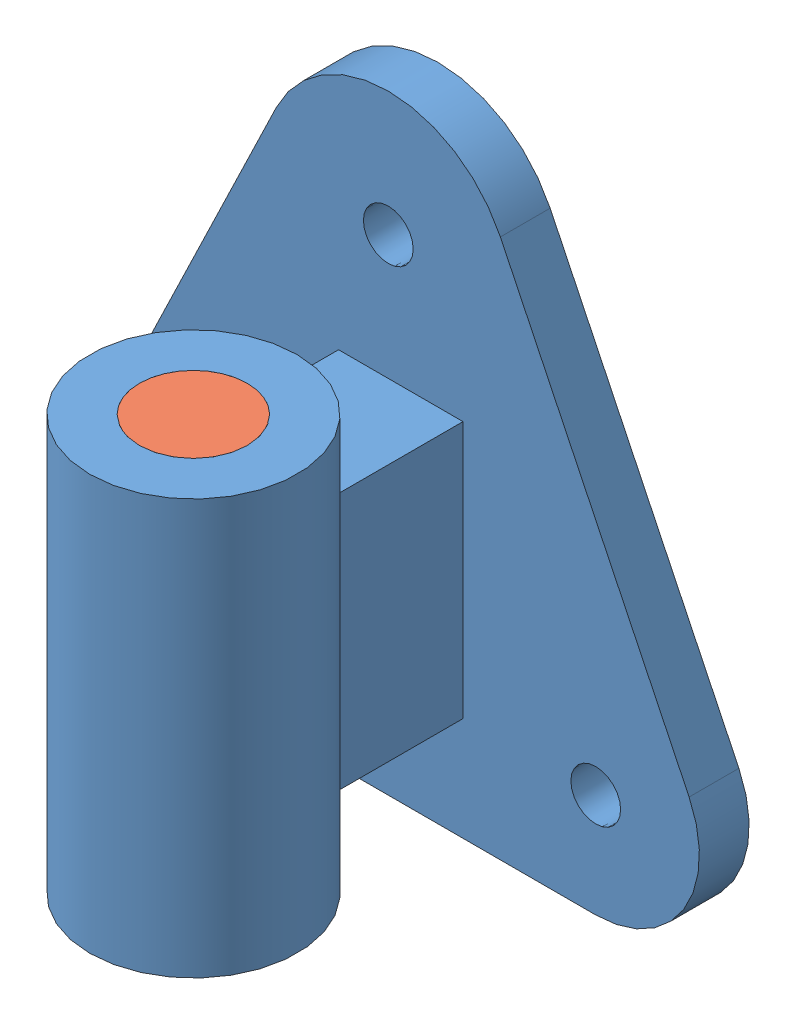
SolidWorks assembly montaj, configuration Varsayılan. Lengths in mm.
Overall size (150 147 87).
2 component instances, 2 part files, 2 mates.
Components (placement in the parent):
- BDTR final ödevi-1: BDTR final ödevi [Varsayılan] at (-85.0786 -73.1239 150) size (150 147 87)
- BDTR final ödevi mil-1: BDTR final ödevi mil [Varsayılan] at (7.7728 -67.1239 212) x (0 0 -1) z (0 1 0) size (26 26 100)
Mates (geometry in assembly coordinates):
- Eş Merkezli1: concentric aligned: cylinder of BDTR final ödevi-1 through (7.7728 13.8761 212) axis (0 -1 0) radius 13; cylinder of BDTR final ödevi mil-1 through (7.7728 32.8761 212) axis (0 -1 0) radius 13
- Çakışık1: coincident aligned: plane of BDTR final ödevi-1 through (7.7728 -67.1239 212) normal (0 -1 0); plane of BDTR final ödevi mil-1 through (7.7728 -67.1239 212) normal (0 -1 0)
